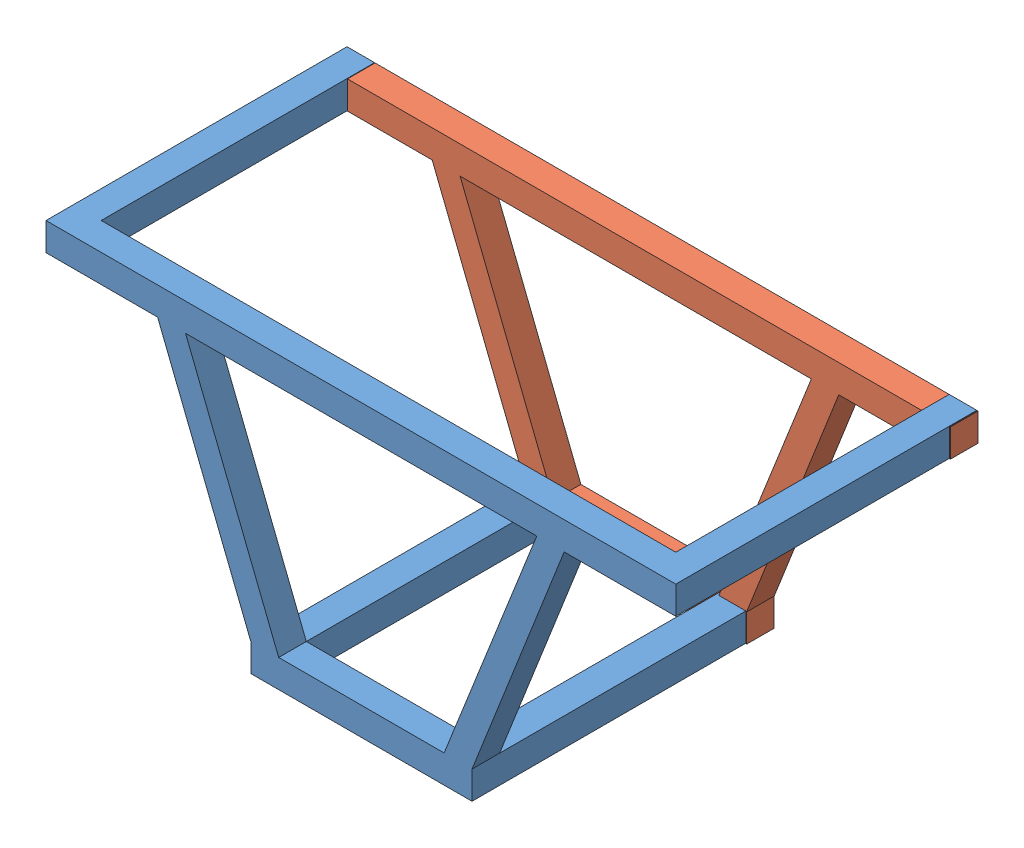
SolidWorks assembly сборка рамы, configuration Default. Lengths in mm.
Overall size (228.32 105.17 109.15).
2 component instances, 2 part files, 0 mates.
Components (placement in the parent):
- рама-4: рама [Default] at (-9.9369 -3.7371 28.6578) size (228.04 105 109)
- рама1-2: рама1 [Default] at (-9.6657 -3.9066 -70.4954) size (228.04 105 10)
